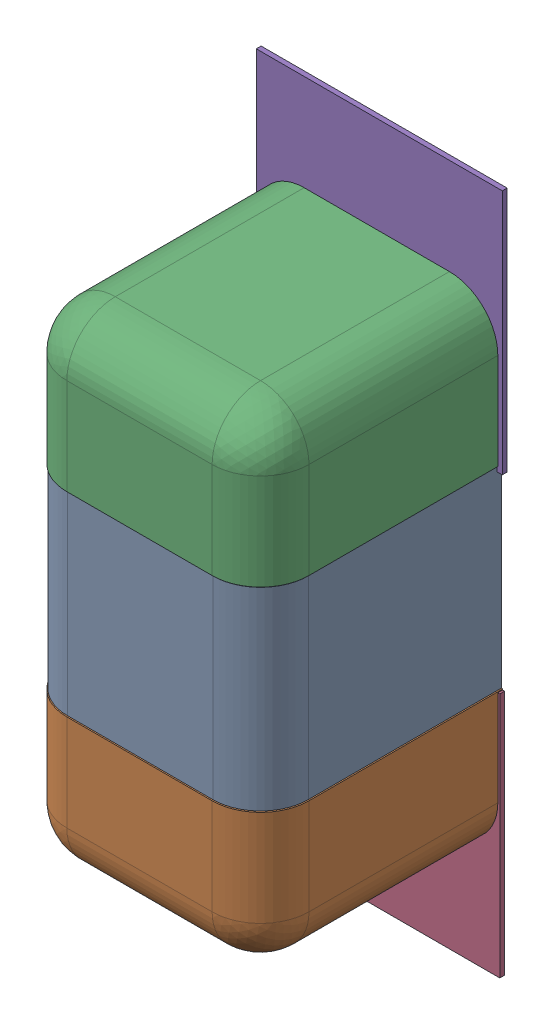
SolidWorks assembly C24, configuration Défaut. Lengths in mm.
Overall size (0.51 1.41 0.5).
8 component instances, 4 part files, 0 mates.
Components (placement in the parent):
- 6501216624-1: 6501216624 [Défaut] at (44.8818 -21.552 0) x (0 1 0) z (1 0 0) size (1 0.5 0.5)
  - Open CASCADE STEP translator 7.5 2.111.1.1-1: Open CASCADE STEP translator 7.5 2.111.1.1 [Défaut] at origin size (0.4 0.5 0.5)
  - Open CASCADE STEP translator 7.5 2.111.1.2-1: Open CASCADE STEP translator 7.5 2.111.1.2 [Défaut] at origin size (0.3 0.5 0.5)
  - Open CASCADE STEP translator 7.5 2.111.1.3-1: Open CASCADE STEP translator 7.5 2.111.1.3 [Défaut] at origin size (0.3 0.5 0.5)
- 6504207776-1: 6504207776 [Défaut] at (44.8818 -22.0093 0) size (0.51 0.51 0.01)
  - Extruded-1: Extruded [Défaut] at origin size (0.51 0.51 0.01)
- 6504207776-2: 6504207776 [Défaut] at (44.887 -21.107 0) size (0.51 0.51 0.01)
  - Extruded-1: Extruded [Défaut] at origin size (0.51 0.51 0.01)
